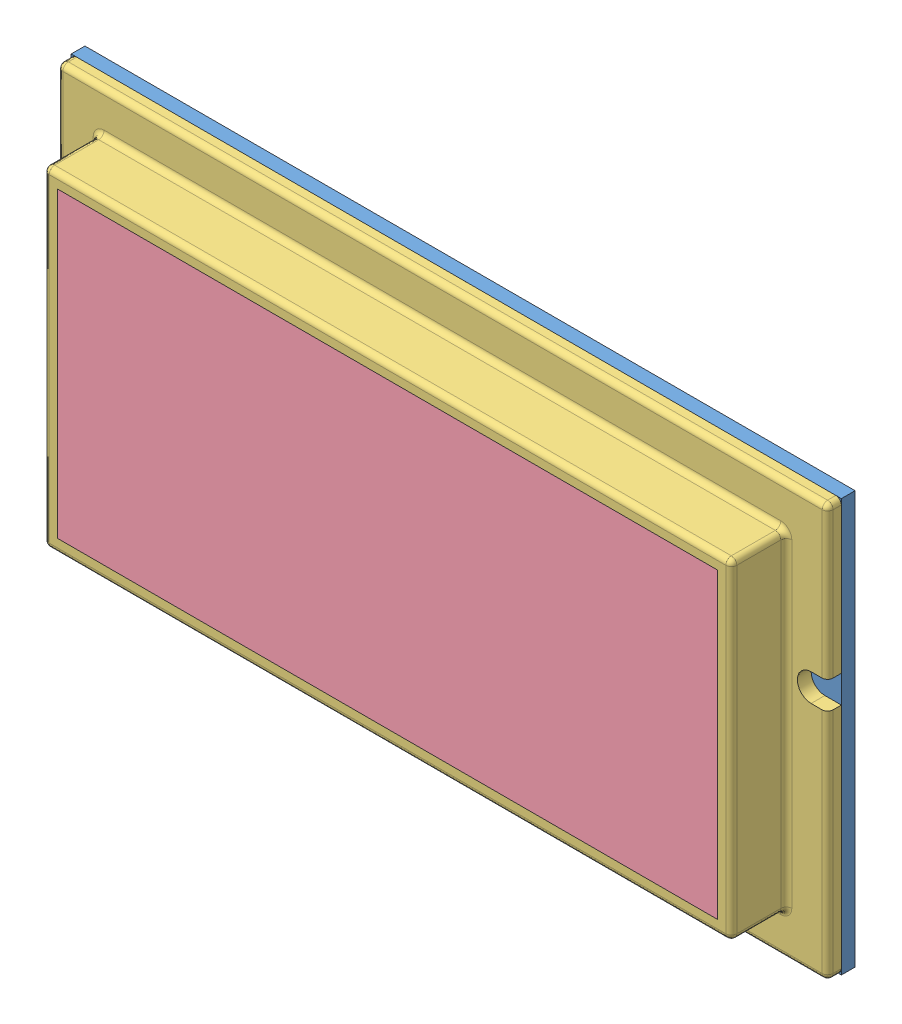
SolidWorks assembly PlaqueModele, configuration Défaut. Lengths in mm.
Overall size (280 150 30).
5 component instances, 5 part files, 8 mates.
Components (placement in the parent):
- PlaqueModele-1: PlaqueModele [Défaut] at (-38.5886 -31.9772 -2.5) size (280 150 5)
- modele2-1: modele2 [Défaut] at (51.4114 43.0228 2.5) size (111.4 41.4 11)
- Chassis-1: Chassis [Défaut] at origin size (280 150 25)
- Moule-1: Moule [Défaut] at (51.4114 43.0228 2.5) size (240 110 25)
- Coulee-1: Coulee [Défaut] at (11.4114 43.0228 2.5) size (35 20 4)
Mates (geometry in assembly coordinates):
- Coïncidente2: coincident anti-aligned: plane of PlaqueModele-1 through (-38.5886 -31.9772 2.5) normal (0 0 1); plane of modele2-1 through (51.4114 43.0228 2.5) normal (0 0 -1)
- Coaxiale1: concentric aligned: cylinder of PlaqueModele-1 through (51.4114 43.0228 -2.5) axis (0 0 1) radius 2.5; cylinder of modele2-1 through (51.4114 43.0228 -0.5) axis (0 0 1) radius 2.5
- Coaxiale2: concentric aligned: cylinder of PlaqueModele-1 through (131.4114 43.0228 -2.5) axis (0 0 1) radius 2.5; cylinder of modele2-1 through (131.4114 43.0228 -0.5) axis (0 0 1) radius 2.5
- Coïncidente1: coincident anti-aligned: plane of PlaqueModele-1 through (-38.5886 -31.9772 2.5) normal (0 0 1); plane of Moule-1 through (-18.5886 -11.9772 2.5) normal (0 0 -1)
- Coaxiale3: concentric aligned: cone of modele2-1 through (51.4114 43.0228 10.5) axis (0 0 1); cone of Moule-1 through (51.4114 43.0228 10.5) axis (0 0 1)
- Coïncidente3: coincident aligned: plane of Chassis-1 through (-38.5886 -31.9772 2.5) normal (0 0 -1); plane of Coulee-1 through (-157.4622 43.0228 2.5) normal (0 0 -1)
- Distance2: distance = 5 mm anti-aligned: plane of assembly through (0 43.0228 0) normal (0 1 0); plane of Coulee-1 through (-499988.5886 38.0228 5.5) normal (0 -1 0)
- Distance3: distance = 55 mm aligned: plane of Coulee-1 through (36.4114 38.0228 5.5) normal (1 0 0); plane of Chassis-1 through (-18.5886 98.0228 7.5) normal (1 0 0)
